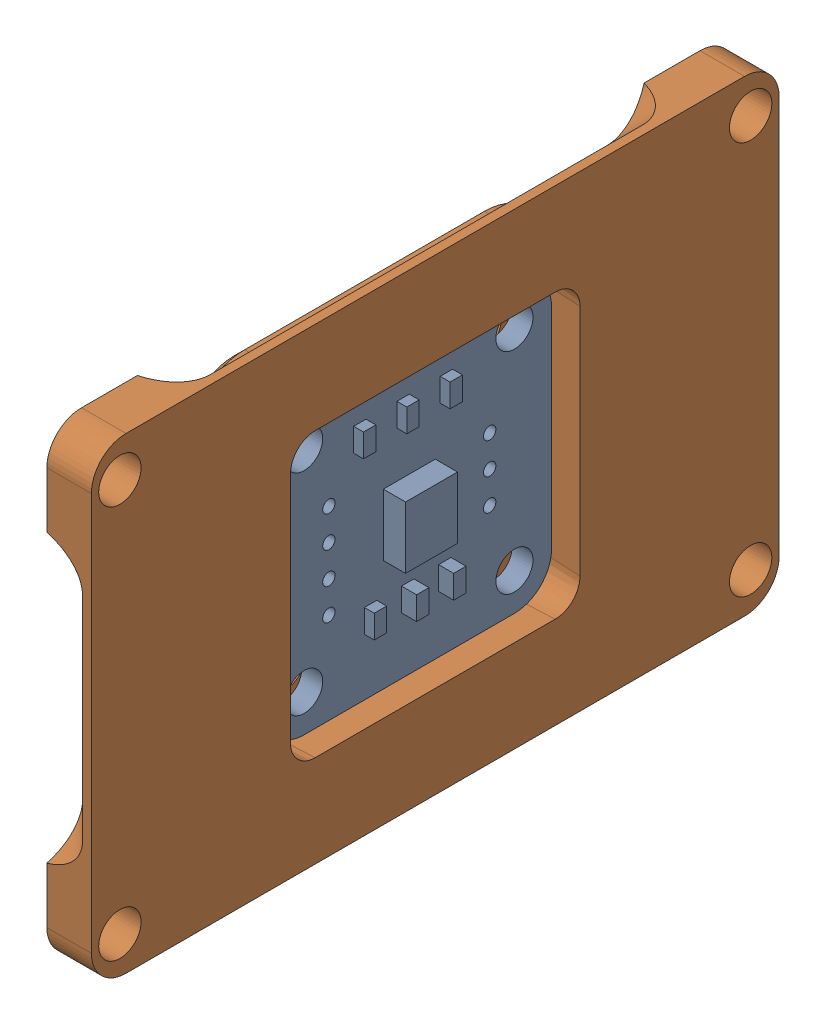
SolidWorks assembly Encoder_2__1, configuration Default. Lengths in mm.
Overall size (6.6 37.8 55.6).
2 component instances, 2 part files, 0 mates.
Components (placement in the parent):
- AS5600_1-1: AS5600_1 [Default] at (-201.6 -23.5 140) x (0 1 0) z (0 0 -1) size (23 3.5 23)
- EncoderHousing_1-1: EncoderHousing_1 [Default] at (-199.3 -23.5 140) x (0 1 0) z (1 0 0) size (37.8 55.6 6.6)
